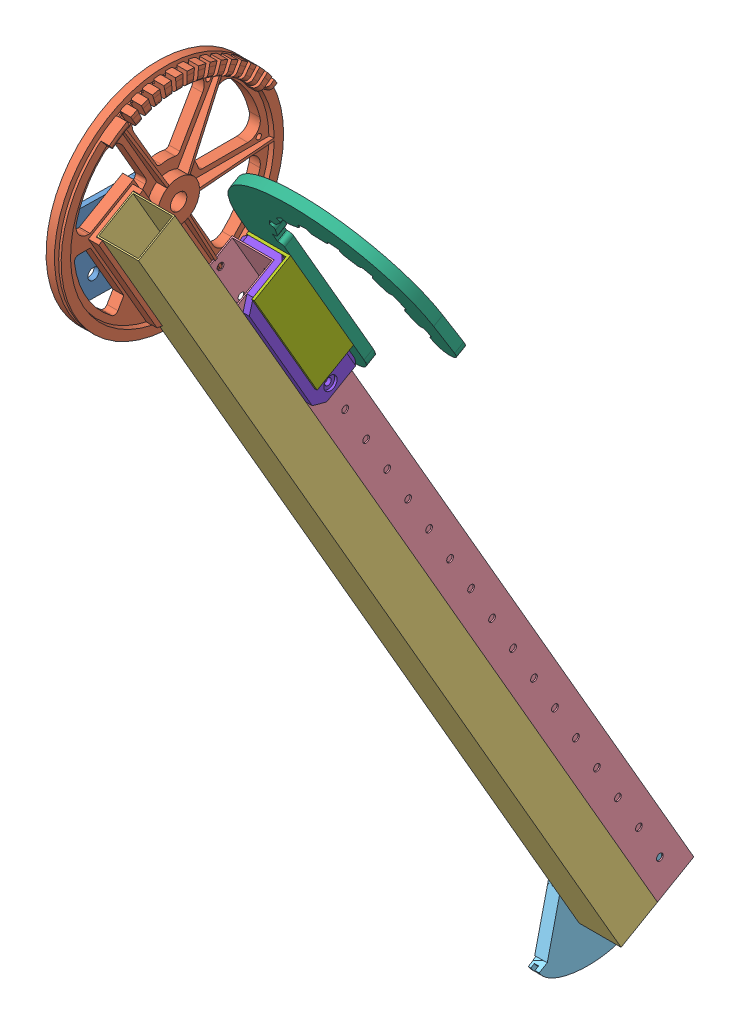
SolidWorks assembly 2018-511-A, configuration Default. Lengths in mm.
Overall size (140.8 636.72 400.32).
8 component instances, 8 part files, 24 mates.
Components (placement in the parent):
- 2018-511-D001-1: 2018-511-D001 [Default] at origin size (3.84 50.8 63.55)
- 2018-511-D003-1: 2018-511-D003 [Default] at (9.779 0 0) x (-1 0 0) z (0 -0.5 0.866025) size (14.37 134.62 134.62)
- 2018-511-D004-1: 2018-511-D004 [Default] at (12.319 -503.112 -246.1845) x (0 0.866025 0.5) z (-1 0 0) size (584.2 25.4 25.4)
- 2018-511-D005-1: 2018-511-D005 [Default] at (12.319 -37.7711 -36.1786) x (0 -0.866025 -0.5) z (-1 0 0) size (508 25.4 25.4)
- 2018-511-D002-1: 2018-511-D002 [Default] at (9.779 -490.412 -268.1815) x (0 0.5 -0.866025) z (-1 0 0) size (81.3 82.77 7.63)
- 2018-511-D006-1: 2018-511-D006 [Default] at (81.153 -23.6802 -41.5347) x (0 -0.5 0.866025) z (-1 0 0) size (6.35 172.72 122.48)
- 2018-511-D007-1: 2018-511-D007 [Default] at (43.053 -101.0952 -78.8979) x (0 0.866025 0.5) z (1 0 0) size (76.2 25.4 25.4)
- 2018-511-D008-1: 2018-511-D008 [Default] at (37.719 -114.7607 -80.6286) x (-1 0 0) z (0 0.5 -0.866025) size (29.21 88.9 29.21)
Mates (geometry in assembly coordinates):
- Coincident1: coincident anti-aligned: plane of 2018-511-D003-1 through (12.319 -52.7929 -30.48) normal (1 0 0); plane of 2018-511-D004-1 through (12.319 2.82 45.9155) normal (-1 0 0)
- Coincident4: coincident aligned: plane of 2018-511-D004-1 through (37.719 2.82 45.9155) normal (1 0 0); plane of 2018-511-D005-1 through (37.719 -477.712 -290.1786) normal (1 0 0)
- Coincident5: coincident aligned: line of 2018-511-D004-1 through (37.719 -490.412 -268.1815) axis (-1 0 0); line of 2018-511-D005-1 through (37.719 -490.412 -268.1815) axis (-1 0 0)
- Coincident6: coincident anti-aligned: plane of 2018-511-D005-1 through (12.319 -477.712 -290.1786) normal (-1 0 0); plane of 2018-511-D002-1 through (12.319 -523.5154 -267.1088) normal (1 0 0)
- Coincident7: coincident anti-aligned: line of 2018-511-D005-1 through (12.319 -477.712 -290.1786) axis (0 0.866025 0.5); line of 2018-511-D002-1 through (12.319 -433.7179 -264.7786) axis (0 -0.866025 -0.5)
- Coincident8: coincident: point of 2018-511-D005-1; point of 2018-511-D002-1
- Concentric2: concentric aligned: cylinder of 2018-511-D001-1 through (3.175 0 0) axis (1 0 0) radius 5.0419; cylinder of 2018-511-D003-1 through (16.129 0 0) axis (1 0 0) radius 4.961
- Coincident13: coincident anti-aligned: plane of 2018-511-D001-1 through (3.175 0 0) normal (1 0 0); plane of 2018-511-D003-1 through (3.175 0 0) normal (-1 0 0)
- LimitAngle1: limit planar angle = 0 rad anti-aligned: plane of 2018-511-D004-1 through (12.319 15.52 23.9185) normal (0 0.5 -0.866025); plane of 2018-511-D005-1 through (12.319 -490.412 -268.1815) normal (0 -0.5 0.866025)
- LimitAngle3: limit planar angle = 2.617994 rad anti-aligned: plane of 2018-511-D004-1 through (12.319 15.52 23.9185) normal (0 0.5 -0.866025); plane of 2018-511-D001-1 through (3.175 12.7 -12.7) normal (0 0 -1)
- Coincident14: coincident anti-aligned: plane of 2018-511-D006-1 through (30.353 -112.0937 -85.2479) normal (0 -0.5 0.866025); plane of 2018-511-D007-1 through (43.053 -35.1041 -40.7979) normal (0 0.5 -0.866025)
- Coincident15: coincident aligned: plane of 2018-511-D006-1 through (43.053 -26.8552 -36.0354) normal (1 0 0); plane of 2018-511-D007-1 through (43.053 -35.1041 -40.7979) normal (1 0 0)
- Distance2: distance = 12.7 mm: plane of 2018-511-D007-1 through (43.053 -101.0952 -78.8979) normal (0 -0.866025 -0.5); point of 2018-511-D006-1
- Distance3: distance = 0 mm anti-aligned: plane of 2018-511-D007-1 through (43.053 -35.8661 -39.4781) normal (0 -0.5 0.866025); plane of 2018-511-D008-1 through (37.719 -35.8661 -39.4781) normal (0 0.5 -0.866025)
- Distance4: distance = 0 mm anti-aligned: plane of 2018-511-D008-1 through (41.529 -50.4711 -14.1815) normal (1 0 0); plane of 2018-511-D007-1 through (41.529 -35.1041 -40.7979) normal (-1 0 0)
- Coincident19: coincident aligned: plane of 2018-511-D005-1 through (12.319 -37.7711 -36.1786) normal (0 0.866025 0.5); plane of 2018-511-D007-1 through (43.053 -35.1041 -40.7979) normal (0 0.866025 0.5)
- Coincident20: coincident anti-aligned: plane of 2018-511-D005-1 through (12.319 -477.712 -290.1786) normal (0 0.5 -0.866025); plane of 2018-511-D008-1 through (37.719 -37.7711 -36.1786) normal (0 -0.5 0.866025)
- Coincident21: coincident anti-aligned: plane of 2018-511-D005-1 through (37.719 -477.712 -290.1786) normal (1 0 0); plane of 2018-511-D008-1 through (37.719 -50.4711 -14.1815) normal (-1 0 0)
- Coincident22: coincident aligned: plane of 2018-511-D005-1 through (12.319 -37.7711 -36.1786) normal (0 0.866025 0.5); plane of 2018-511-D008-1 through (37.719 -37.7711 -36.1786) normal (0 0.866025 0.5)
- Coincident24: coincident aligned: plane of 2018-511-D001-1 through (0 0 0) normal (0 0 1); plane of assembly through (0 0 0) normal (0 0 1)
- Distance5: distance = 0.254 mm anti-aligned: plane of 2018-511-D004-1 through (12.319 2.82 45.9155) normal (0 -0.5 0.866025); plane of 2018-511-D003-1 through (9.779 2.693 46.1355) normal (0 0.5 -0.866025)
- Coincident30: coincident aligned: plane of 2018-511-D003-1 through (9.779 21.997 12.7) normal (0 0.866025 0.5); plane of 2018-511-D004-1 through (12.319 2.82 45.9155) normal (0 0.866025 0.5)
- Coincident33: coincident aligned: plane of 2018-511-D001-1 through (0 0 0) normal (0 1 0); plane of assembly through (0 0 0) normal (0 1 0)
- Coincident34: coincident aligned: plane of 2018-511-D001-1 through (0 0 0) normal (1 0 0); plane of assembly through (0 0 0) normal (1 0 0)
